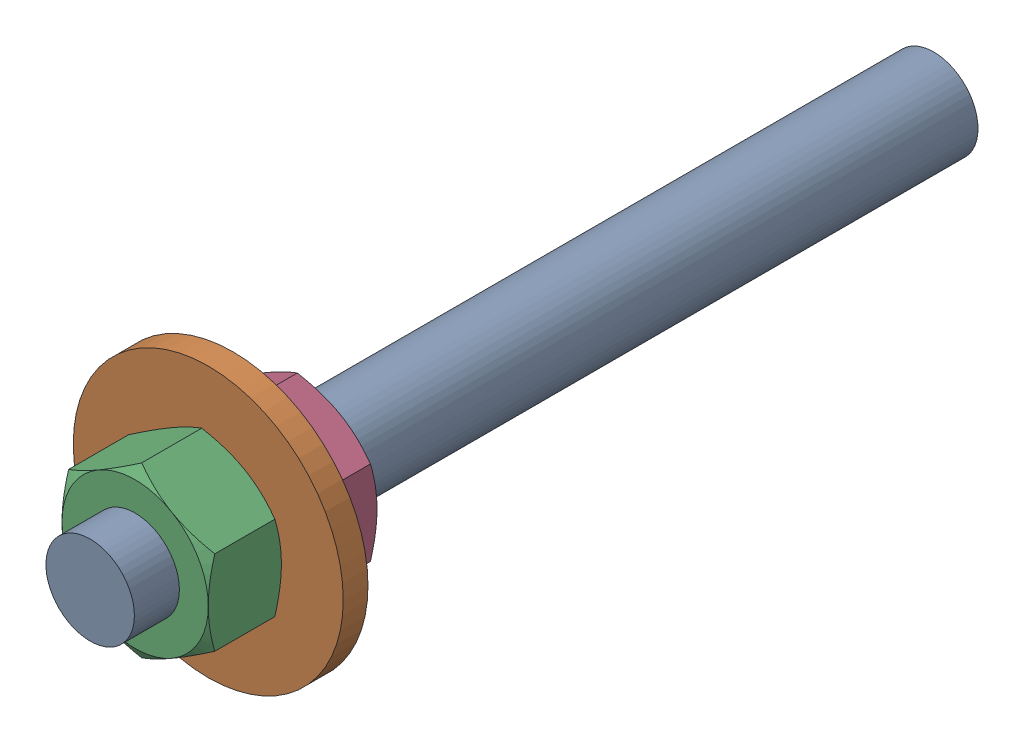
SolidWorks assembly SSDCT Threaded Rod Sub Asmbly, configuration Default. Lengths in mm.
Overall size (24 24 75).
4 component instances, 3 part files, 0 mates.
Components (placement in the parent):
- SSDCT Fixed End M8 Threaded Rod-1: SSDCT Fixed End M8 Threaded Rod [Default] at origin size (7.87 7.87 75)
- 8.4mm ID 24mm OD Flat Washer-1: 8.4mm ID 24mm OD Flat Washer [Default] at (0 0 22.3) size (24 24 2.2)
- M8 x 1.25 Hex Nut-1: M8 x 1.25 Hex Nut [Default] at (0 0 27.75) size (13 15.01 6.5)
- M8 x 1.25 Hex Nut-2: M8 x 1.25 Hex Nut [Default] at (0 0 19.25) size (13 15.01 6.5)
